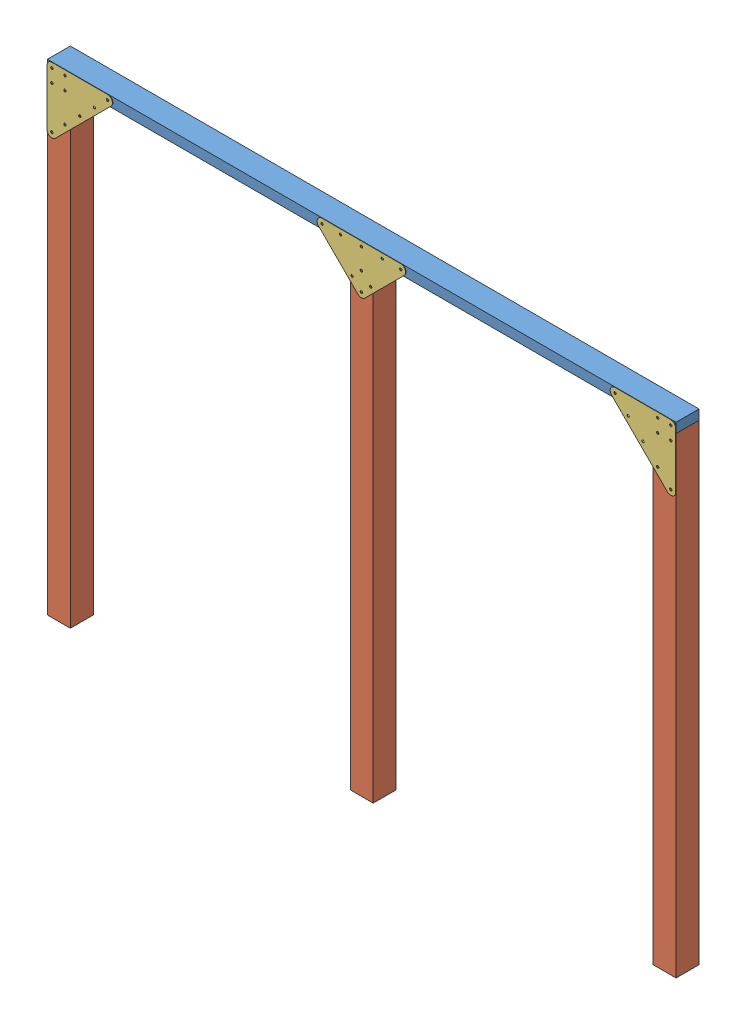
SolidWorks assembly stringer_6ft, configuration Default. Lengths in mm.
Overall size (2670.08 1982.74 90.54).
7 component instances, 3 part files, 8 mates.
Components (placement in the parent):
- 2x4x8ft-1: 2x4x8ft [Default] at (1909.8971 1548.5847 1768.4217) size (2438.4 38.1 88.9)
- 4x4x6ft-1: 4x4x6ft [Default] at (-439.6029 -318.3153 1857.3217) size (88.9 1828.8 88.9)
- 4x4x6ft-2: 4x4x6ft [Default] at (1909.8971 -318.3153 1857.3217) size (88.9 1828.8 88.9)
- bracket-1: bracket [Default] at (1628.9563 1548.5847 1857.3217) x (-0.707107 0.707107 0) z (0 0 1) size (343.43 190.77 1.64)
- bracket-2: bracket [Default] at (-528.5029 1267.6439 1857.3217) x (-0.707107 -0.707107 0) z (0 0 1) size (343.43 190.77 1.64)
- 4x4x6ft-3: 4x4x6ft [Default] at (735.1471 -318.3153 1857.3217) size (88.9 1828.8 88.9)
- bracket-3: bracket [Default] at (889.4916 1548.5847 1857.3217) size (343.43 190.77 1.64)
Mates (geometry in assembly coordinates):
- Coincident3: coincident: point of 2x4x8ft-1; unknown of 4x4x6ft-1
- Coincident4: coincident: unknown of 2x4x8ft-1; unknown of 4x4x6ft-2
- Coincident6: coincident aligned: line of 4x4x6ft-2 through (1909.8971 1510.4847 1857.3217) axis (0 -1 0); line of bracket-1 through (1909.8971 1529.5347 1857.3217) axis (0 -1 0)
- Coincident7: coincident aligned: line of 2x4x8ft-1 through (1909.8971 1548.5847 1857.3217) axis (-1 0 0); line of bracket-1 through (1890.8471 1548.5847 1857.3217) axis (-1 0 0)
- Coincident8: coincident anti-aligned: line of 2x4x8ft-1 through (1909.8971 1548.5847 1857.3217) axis (-1 0 0); line of bracket-2 through (-509.4529 1548.5847 1857.3217) axis (1 0 0)
- Coincident9: coincident aligned: line of 4x4x6ft-1 through (-528.5029 1510.4847 1857.3217) axis (0 -1 0); line of bracket-2 through (-528.5029 1529.5347 1857.3217) axis (0 -1 0)
- Coincident11: coincident: unknown of 4x4x6ft-3
- Coincident12: coincident: unknown of 2x4x8ft-1; unknown of bracket-3
